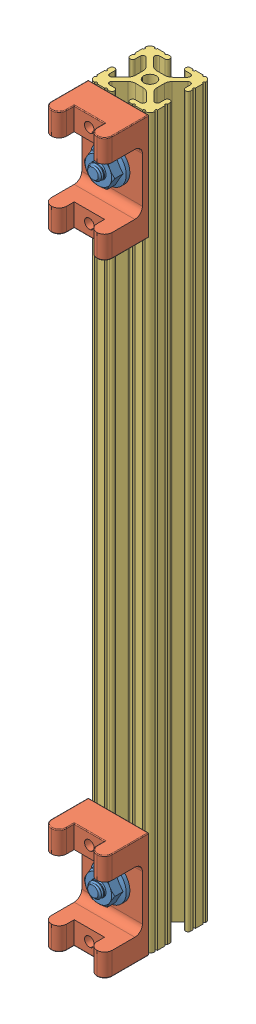
SolidWorks assembly mount_rail, configuration Default. Lengths in mm.
Overall size (25.4 304.8 44.45).
5 component instances, 3 part files, 10 mates.
Components (placement in the parent):
- 47065T233_ALUMINUM T-SLOTTED FRAMING EXTRUSION-1: 47065T233_ALUMINUM T-SLOTTED FRAMING EXTRUSION [47065T233] at (-19.5403 55.558 33.4144) x (1 0 0) z (0 -1 0) size (14.83 17.81 14.83)
- extrusion_mount-1: extrusion_mount [Default] at (-19.5403 33.333 44.5269) size (25.4 44.45 19.05)
- MCMASTER_47065T411_ALUMINUM T-SLOTTED FRAMING EXTRUSION-1: MCMASTER_47065T411_ALUMINUM T-SLOTTED FRAMING EXTRUSION [47065T411] at (-19.5403 -74.617 22.3019) x (1 0 0) z (0 -1 0) size (25.4 25.4 304.8)
- extrusion_mount-3: extrusion_mount [Default] at (-19.5403 -227.017 44.5269) size (25.4 44.45 19.05)
- 47065T233_ALUMINUM T-SLOTTED FRAMING EXTRUSION-2: 47065T233_ALUMINUM T-SLOTTED FRAMING EXTRUSION [47065T233] at (-19.5403 -204.792 33.4144) x (1 0 0) z (0 -1 0) size (14.83 17.81 14.83)
Mates (geometry in assembly coordinates):
- Coincident1: coincident anti-aligned: plane of extrusion_mount-1 through (-32.2403 77.783 35.0019) normal (0 0 -1); plane of MCMASTER_47065T411_ALUMINUM T-SLOTTED FRAMING EXTRUSION-1 through (-9.9898 -227.017 35.0019) normal (0 0 1)
- Coincident2: coincident aligned: plane of extrusion_mount-1 through (-19.5403 77.783 44.5269) normal (0 1 0); plane of MCMASTER_47065T411_ALUMINUM T-SLOTTED FRAMING EXTRUSION-1 through (-25.9567 77.783 12.892) normal (0 1 0)
- Coincident3: coincident aligned: plane of extrusion_mount-1 through (-32.2403 77.783 35.0019) normal (-1 0 0); plane of MCMASTER_47065T411_ALUMINUM T-SLOTTED FRAMING EXTRUSION-1 through (-32.2403 -227.017 31.8523) normal (-1 0 0)
- Concentric1: concentric aligned: cylinder of 47065T233_ALUMINUM T-SLOTTED FRAMING EXTRUSION-1 through (-19.5403 55.558 46.2019) axis (0 0 1) radius 7.4168; cylinder of extrusion_mount-1 through (-19.5403 55.558 38.1769) axis (0 0 1) radius 3.175
- Coincident4: coincident anti-aligned: plane of 47065T233_ALUMINUM T-SLOTTED FRAMING EXTRUSION-1 through (-13.1245 55.558 38.1769) normal (0 0 -1); plane of extrusion_mount-1 through (-32.2403 42.858 38.1769) normal (0 0 1)
- Concentric2: concentric aligned: cylinder of 47065T233_ALUMINUM T-SLOTTED FRAMING EXTRUSION-2 through (-19.5403 -204.792 46.2019) axis (0 0 1) radius 7.4168; cylinder of extrusion_mount-3 through (-19.5403 -204.792 38.1769) axis (0 0 1) radius 3.175
- Coincident5: coincident anti-aligned: plane of extrusion_mount-3 through (-32.2403 -217.492 38.1769) normal (0 0 1); plane of 47065T233_ALUMINUM T-SLOTTED FRAMING EXTRUSION-2 through (-13.1245 -204.792 38.1769) normal (0 0 -1)
- Coincident6: coincident anti-aligned: plane of MCMASTER_47065T411_ALUMINUM T-SLOTTED FRAMING EXTRUSION-1 through (-25.8734 -227.017 35.0019) normal (0 0 1); plane of extrusion_mount-3 through (-32.2403 -182.567 35.0019) normal (0 0 -1)
- Coincident7: coincident aligned: plane of MCMASTER_47065T411_ALUMINUM T-SLOTTED FRAMING EXTRUSION-1 through (-32.2403 -227.017 31.8523) normal (-1 0 0); plane of extrusion_mount-3 through (-32.2403 -182.567 35.0019) normal (-1 0 0)
- Coincident8: coincident aligned: plane of MCMASTER_47065T411_ALUMINUM T-SLOTTED FRAMING EXTRUSION-1 through (-25.9567 -227.017 12.892) normal (0 -1 0); plane of extrusion_mount-3 through (-19.5403 -227.017 44.5269) normal (0 -1 0)
